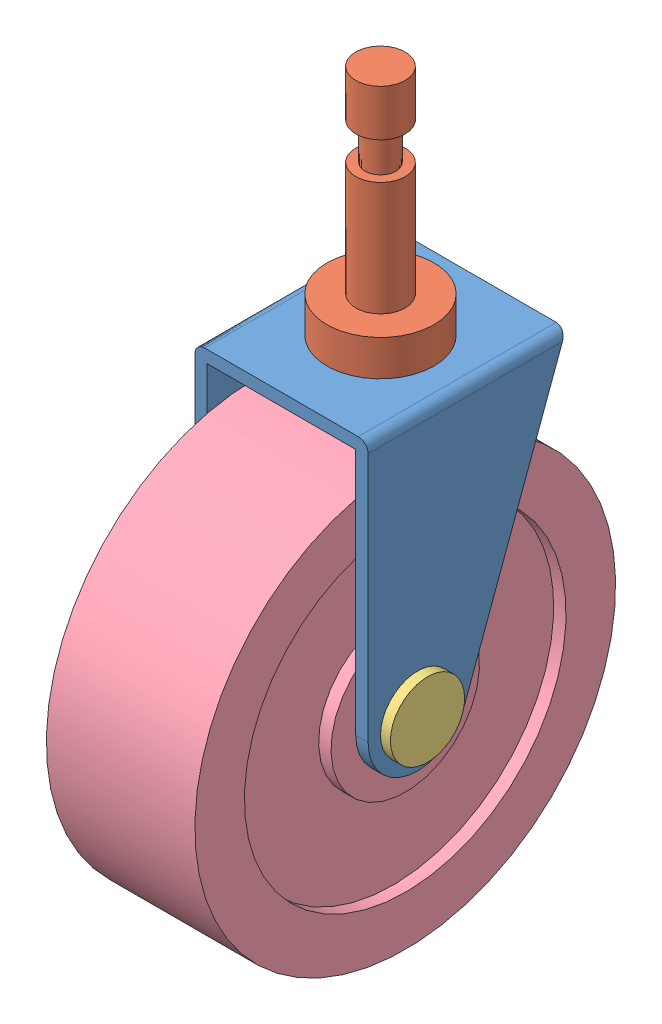
SolidWorks assembly LLanta, configuration Predeterminado. Lengths in mm.
Overall size (59.69 193.71 134.56).
4 component instances, 4 part files, 6 mates.
Components (placement in the parent):
- Casita-llanta-1: Casita-llanta [Predeterminado] at (-37.8303 -31.4814 53.975) size (44.45 79.38 50.8)
- superior-1: superior [Predeterminado] at (-18.7803 41.6749 79.375) x (0.490934 0 -0.871197) z (0.871197 0 0.490934) size (27.48 65.97 27.48)
- tornillo llanta-1: tornillo llanta [Predeterminado] at (5.9847 -18.7814 92.075) x (0 0.2849 -0.958557) z (0 0.958557 0.2849) size (19.05 59.69 19.05)
- llanta buena-1: llanta buena [Predeterminado] at (-37.8303 -18.7814 92.075) x (1 0 0) z (0 -0.957262 -0.289221) size (38.1 107.95 107.95)
Mates (geometry in assembly coordinates):
- Concéntrica1: concentric aligned: circle of Casita-llanta-1; circle of llanta buena-1
- Coincidente3: coincident aligned: circle of Casita-llanta-1; circle of llanta buena-1
- Concéntrica2: concentric aligned: circle of tornillo llanta-1; circle of llanta buena-1
- Coincidente6: coincident anti-aligned: plane of Casita-llanta-1 through (3.4447 47.8936 104.775) normal (1 0 0); plane of tornillo llanta-1 through (3.4447 -18.7814 92.075) normal (-1 0 0)
- Concéntrica3: concentric anti-aligned: circle of Casita-llanta-1; circle of superior-1
- Coincidente7: coincident anti-aligned: plane of Casita-llanta-1 through (-41.0053 47.8936 104.775) normal (0 1 0); circle of superior-1
